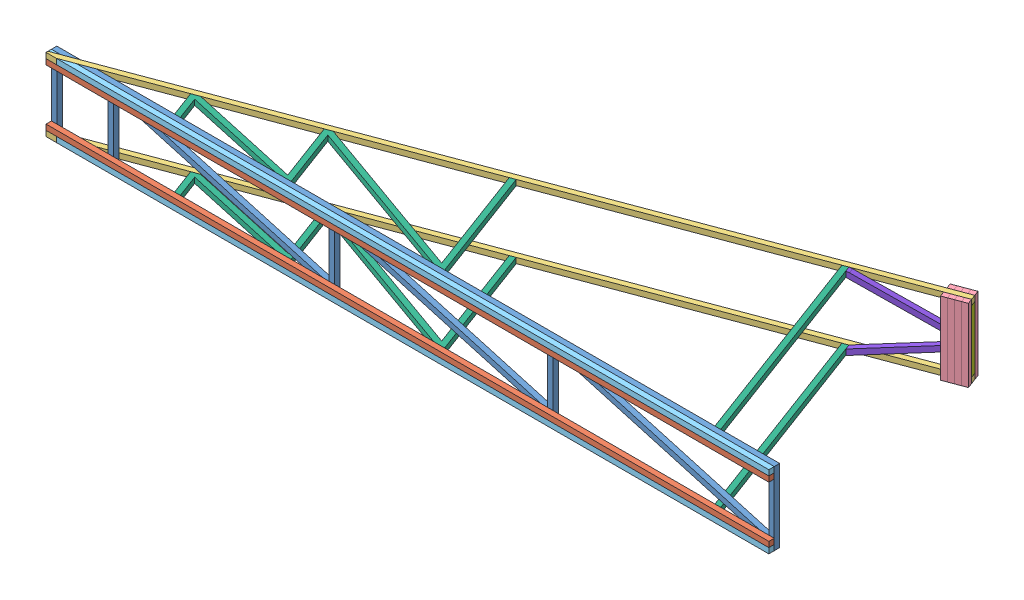
SolidWorks assembly boomAssembly3_1, configuration Default. Lengths in mm.
Overall size (423.17 42.7 151.68).
22 component instances, 9 part files, 96 mates.
Components (placement in the parent):
- cross brace compressionnew-1: cross brace compressionnew [Default] at (-109.2004 207.2528 347.8228) size (423.18 42.7 3.17)
- Part1-1: Part1 [Default] at (-109.2004 207.2528 354.1728) size (423.18 36.35 3.17)
- tension members-3: tension members [Default] at (269.1249 227.7278 350.9978) x (-1 0 0) z (0 0 1) size (396.18 3.18 148.71)
- tension members-4: tension members [Default] at (269.1249 267.2528 350.9978) x (-1 0 0) z (0 0 1) size (396.18 3.18 148.71)
- jHookMount-1: jHookMount [Default] at (264.7186 215.9028 209.7497) x (0.936777 0 -0.349926) z (0 1 0) size (3.17 3.17 42.7)
- jHookMount-2: jHookMount [Default] at (266.9407 215.9028 215.6982) x (0.936777 0 -0.349926) z (0 1 0) size (3.17 3.17 42.7)
- Part1^boomAssembly3_1-1: Part1^boomAssembly3_1 [Default] at origin (virtual)
- Part2^boomAssembly3_1-1: Part2^boomAssembly3_1 [Default] at (269.1249 258.6028 350.9978) x (1 0 0) z (0 1 0) size (423.17 3.17 3.17) (virtual)
- Part4^boomAssembly3_1-1: Part4^boomAssembly3_1 [Default] at (269.1249 258.6028 350.9978) x (1 0 0) z (0 1 0) size (325.36 119.85 3.17) (virtual)
- Part2^boomAssembly3_1-2: Part2^boomAssembly3_1 [Default] at (269.1249 219.0778 350.9978) x (1 0 0) z (0 1 0) size (423.17 3.17 3.17) (virtual)
- Part4^boomAssembly3_1-2: Part4^boomAssembly3_1 [Default] at (269.1249 219.0778 350.9978) x (1 0 0) z (0 1 0) size (325.36 119.85 3.17) (virtual)
- jHookMount-8: jHookMount [Default] at (261.7444 215.9028 210.8607) x (0.936777 0 -0.349926) z (0 1 0) size (3.17 3.17 42.7)
- jHookMount-9: jHookMount [Default] at (265.8296 215.9028 212.724) x (-0.936777 0 0.349926) z (0 1 0) size (3.17 3.17 42.7)
- jHookMount-10: jHookMount [Default] at (258.7701 215.9028 211.9717) x (0.936777 0 -0.349926) z (0 1 0) size (3.17 3.17 42.7)
- jHookMount-11: jHookMount [Default] at (260.9921 215.9028 217.9203) x (0.936777 0 -0.349926) z (0 1 0) size (3.17 3.17 42.7)
- Part5^boomAssembly3_1-1: Part5^boomAssembly3_1 [Default] at (267.6929 215.9028 208.6387) x (0 -1 0) z (0.936777 0 -0.349926) size (36.35 3.17 3.17) (virtual)
- Part5^boomAssembly3_1-2: Part5^boomAssembly3_1 [Default] at (264.7186 215.9028 209.7497) x (0 -1 0) z (0.936777 0 -0.349926) size (36.35 3.17 3.17) (virtual)
- Part5^boomAssembly3_1-3: Part5^boomAssembly3_1 [Default] at (261.7444 215.9028 210.8607) x (0 -1 0) z (0.936777 0 -0.349926) size (36.35 3.17 3.17) (virtual)
- jHookMount-16: jHookMount [Default] at (258.0179 215.9028 219.0313) x (0.936777 0 -0.349926) z (0 1 0) size (3.17 3.17 42.7)
- jHookMount-17: jHookMount [Default] at (255.7958 215.9028 213.0827) x (0.936777 0 -0.349926) z (0 1 0) size (3.17 3.17 42.7)
- Part9^boomAssembly3_1-1: Part9^boomAssembly3_1 [Default] at (223.3948 267.2528 228.5752) x (-0.936777 0 0.349926) z (0.349926 0 0.936777) size (43.13 42.7 3.17) (virtual)
- Part5^boomAssembly3_1-5: Part5^boomAssembly3_1 [Default] at (258.7701 215.9028 211.9717) x (0 -1 0) z (0.936777 0 -0.349926) size (36.35 3.17 3.17) (virtual)
Mates (geometry in assembly coordinates):
- Coincident4: coincident: plane of cross brace compressionnew-1 through (-127.3754 207.2528 350.9978) normal (-1 0 0); plane of Part1-1 through (-127.3754 207.2528 357.3478) normal (-1 0 0)
- Coincident5: coincident: plane of cross brace compressionnew-1 through (-109.2004 207.2528 354.1728) normal (0 0 1); plane of Part1-1 through (-109.2004 207.2528 354.1728) normal (0 0 -1)
- Coincident7: coincident: plane of Part1-1 through (-109.2004 207.2528 357.3478) normal (0 0 1); plane of tension members-3 through (291.79 227.7278 357.3478) normal (0 0 1)
- Coincident8: coincident: plane of cross brace compressionnew-1 through (-107.5644 219.0778 352.2026) normal (-0.349926 0 -0.936777); plane of tension members-3 through (223.3948 176.3778 228.5752) normal (0.349926 0 0.936777)
- Coincident9: coincident: plane of Part1-1 through (-109.2004 219.0778 357.3478) normal (0 -1 0); plane of tension members-3 through (291.79 219.0778 350.9978) normal (0 1 0)
- Coincident10: coincident: plane of cross brace compressionnew-1 through (-108.6754 255.4278 349.2284) normal (0.349926 0 0.936777); plane of tension members-4 through (222.2837 215.9028 225.6009) normal (-0.349926 0 -0.936777)
- Coincident11: coincident: plane of Part1-1 through (-109.2004 207.2528 357.3478) normal (0 0 1); plane of tension members-4 through (291.79 267.2528 357.3478) normal (0 0 1)
- Coincident12: coincident: plane of cross brace compressionnew-1 through (-131.8656 258.6028 347.8228) normal (0 1 0); plane of tension members-4 through (291.79 258.6028 350.9978) normal (0 1 0)
- Coincident13: coincident: plane of cross brace compressionnew-1 through (-131.8656 219.0778 347.8228) normal (0 1 0); plane of Part1-1 through (-109.2004 219.0778 357.3478) normal (0 -1 0)
- Coincident14: coincident: plane of tension members-3 through (222.2837 176.3778 225.6009) normal (-0.349926 0 -0.936777); plane of jHookMount-1 through (264.7186 258.6028 209.7497) normal (0.349926 0 0.936777)
- Coincident15: coincident: plane of tension members-4 through (291.79 258.6028 350.9978) normal (0 1 0); plane of jHookMount-1 through (264.7186 258.6028 209.7497) normal (0 1 0)
- Coincident17: coincident: plane of tension members-3 through (223.3948 176.3778 228.5752) normal (0.349926 0 0.936777); plane of jHookMount-2 through (265.8296 258.6028 212.724) normal (-0.349926 0 -0.936777)
- Coincident19: coincident: plane of tension members-3 through (291.79 215.9028 350.9978) normal (0 -1 0); plane of jHookMount-2 through (266.9407 215.9028 215.6982) normal (0 -1 0)
- InPlace1: in place: plane of tension members-4 through (291.79 258.6028 350.9978) normal (0 1 0); plane of ? through (0 258.6028 0) normal (0 1 0); moOrthogonalPlaneRef_w of tension members-4 through (291.79 258.6028 350.9978) normal (0 1 0); plane of ? through (0 258.6028 0) normal (0 0 -1); plane of tension members-4 through (291.79 258.6028 350.9978) normal (0 1 0); plane of ? through (0 258.6028 0) normal (1 0 0); plane of tension members-4 through (291.79 258.6028 350.9978) normal (0 1 0); unknown of ?
- Coincident20: coincident: plane of tension members-4; plane of Part2^boomAssembly3_1-1
- Coincident21: coincident: moOrthogonalPlaneRef_w of tension members-4 through (269.1249 258.6028 350.9978) normal (0 0 -1); plane of Part2^boomAssembly3_1-1 through (269.1249 258.6028 350.9978) normal (0 0 -1)
- Coincident22: coincident: moOrthogonalPlaneRef_w of tension members-4 through (269.1249 258.6028 350.9978) normal (-1 0 0); plane of Part2^boomAssembly3_1-1 through (269.1249 258.6028 350.9978) normal (1 0 0)
- Coincident23: coincident: plane of Part1-1 through (-109.2004 222.2528 357.3478) normal (0 1 0); plane of ? through (-109.2004 222.2528 360.5228) normal (0 1 0)
- Coincident24: coincident: plane of Part1-1 through (-109.2004 207.2528 357.3478) normal (0 0 1); plane of ? through (-109.2004 207.2528 357.3478) normal (0 0 -1)
- Coincident25: coincident: plane of cross brace compressionnew-1 through (-127.3754 207.2528 350.9978) normal (-1 0 0); plane of ? through (-127.3754 207.2528 360.5228) normal (-1 0 0)
- InPlace2: in place: plane of ? through (-127.3754 207.2528 360.5228) normal (-1 0 0); plane of ? through (-127.3754 0 0) normal (-1 0 0); plane of ? through (-127.3754 207.2528 360.5228) normal (-1 0 0); plane of ? through (-127.3754 0 0) normal (0 1 0); plane of ? through (-127.3754 207.2528 360.5228) normal (-1 0 0); plane of ? through (-127.3754 0 0) normal (0 0 1); plane of ? through (-127.3754 207.2528 360.5228) normal (-1 0 0); unknown of ?
- Coincident26: coincident: plane of ?; plane of ?
- Coincident27: coincident: moOrthogonalPlaneRef_w of ? through (-127.3754 207.2528 357.3478) normal (0 1 0); plane of ? through (-127.3754 207.2528 357.3478) normal (0 1 0)
- Coincident28: coincident: moOrthogonalPlaneRef_w of ? through (-127.3754 207.2528 357.3478) normal (0 0 -1); plane of ? through (-127.3754 207.2528 357.3478) normal (0 0 1)
- InPlace3: in place: plane of tension members-4 through (291.79 258.6028 350.9978) normal (0 1 0); plane of ? through (0 258.6028 0) normal (0 1 0); plane of tension members-4 through (291.79 258.6028 350.9978) normal (0 1 0); plane of ? through (0 258.6028 0) normal (0 0 -1); plane of tension members-4 through (291.79 258.6028 350.9978) normal (0 1 0); plane of ? through (0 258.6028 0) normal (1 0 0); plane of tension members-4 through (291.79 258.6028 350.9978) normal (0 1 0); unknown of ?
- Coincident29: coincident: plane of tension members-4; plane of Part4^boomAssembly3_1-1
- Coincident30: coincident: moOrthogonalPlaneRef_w of tension members-4 through (269.1249 258.6028 350.9978) normal (0 0 -1); plane of Part4^boomAssembly3_1-1 through (269.1249 258.6028 350.9978) normal (0 0 -1)
- Coincident31: coincident: moOrthogonalPlaneRef_w of tension members-4 through (269.1249 258.6028 350.9978) normal (-1 0 0); plane of Part4^boomAssembly3_1-1 through (269.1249 258.6028 350.9978) normal (1 0 0)
- Coincident32: coincident: plane of tension members-4 through (314.534 267.2528 334.0356) normal (0.936777 0 -0.349926); plane of jHookMount-1 through (267.6929 258.6028 208.6387) normal (0.936777 0 -0.349926)
- Coincident33: coincident: plane of tension members-4 through (314.534 267.2528 334.0356) normal (0.936777 0 -0.349926); plane of jHookMount-2 through (269.9149 258.6028 214.5872) normal (0.936777 0 -0.349926)
- Coincident34: coincident: plane of tension members-4 through (223.3948 215.9028 228.5752) normal (0.349926 0 0.936777); plane of jHookMount-11 through (259.8811 258.6028 214.946) normal (-0.349926 0 -0.936777)
- Coincident35: coincident: plane of tension members-4 through (223.3948 215.9028 228.5752) normal (0.349926 0 0.936777); plane of jHookMount-9 through (265.8296 258.6028 212.724) normal (-0.349926 0 -0.936777)
- Coincident36: coincident: plane of tension members-3 through (291.79 215.9028 350.9978) normal (0 -1 0); plane of jHookMount-9 through (265.8296 215.9028 212.724) normal (0 -1 0)
- Coincident37: coincident: plane of tension members-3 through (291.79 215.9028 350.9978) normal (0 -1 0); plane of jHookMount-11 through (260.9921 215.9028 217.9203) normal (0 -1 0)
- Coincident38: coincident: plane of tension members-3 through (222.2837 176.3778 225.6009) normal (-0.349926 0 -0.936777); plane of jHookMount-8 through (261.7444 258.6028 210.8607) normal (0.349926 0 0.936777)
- Coincident39: coincident: plane of tension members-3 through (222.2837 176.3778 225.6009) normal (-0.349926 0 -0.936777); plane of jHookMount-10 through (258.7701 258.6028 211.9717) normal (0.349926 0 0.936777)
- Coincident40: coincident: plane of tension members-3 through (291.79 215.9028 350.9978) normal (0 -1 0); plane of jHookMount-8 through (261.7444 215.9028 210.8607) normal (0 -1 0)
- Coincident41: coincident: plane of tension members-3 through (291.79 215.9028 350.9978) normal (0 -1 0); plane of jHookMount-10 through (258.7701 215.9028 211.9717) normal (0 -1 0)
- Coincident42: coincident: plane of jHookMount-1 through (264.7186 258.6028 209.7497) normal (-0.936777 0 0.349926); plane of jHookMount-8 through (264.7186 258.6028 209.7497) normal (0.936777 0 -0.349926)
- Coincident43: coincident: plane of jHookMount-8 through (261.7444 258.6028 210.8607) normal (-0.936777 0 0.349926); plane of jHookMount-10 through (261.7444 258.6028 210.8607) normal (0.936777 0 -0.349926)
- Coincident44: coincident: plane of jHookMount-2 through (266.9407 258.6028 215.6982) normal (-0.936777 0 0.349926); plane of jHookMount-9 through (265.8296 258.6028 212.724) normal (0.936777 0 -0.349926)
- Coincident45: coincident: plane of jHookMount-9 through (262.8554 258.6028 213.835) normal (-0.936777 0 0.349926); plane of jHookMount-11 through (263.9664 258.6028 216.8092) normal (0.936777 0 -0.349926)
- InPlace4: in place: plane of jHookMount-8 through (264.7186 258.6028 209.7497) normal (0.936777 0 -0.349926); plane of ? through (163.5476 0 -61.092) normal (0.936777 0 -0.349926); plane of jHookMount-8 through (264.7186 258.6028 209.7497) normal (0.936777 0 -0.349926); plane of ? through (163.5476 0 -61.092) normal (0 1 0); plane of jHookMount-8 through (264.7186 258.6028 209.7497) normal (0.936777 0 -0.349926); plane of ? through (163.5476 0 -61.092) normal (-0.349926 0 -0.936777); plane of jHookMount-1 through (267.6929 258.6028 208.6387) normal (0.936777 0 -0.349926); unknown of Part5^boomAssembly3_1-1
- Coincident46: coincident: plane of ?; plane of Part5^boomAssembly3_1-1
- Coincident47: coincident: moOrthogonalPlaneRef_w of jHookMount-1 through (267.6929 215.9028 208.6387) normal (-0.349926 0 -0.936777); plane of Part5^boomAssembly3_1-1 through (267.6929 215.9028 208.6387) normal (-0.349926 0 -0.936777)
- Coincident48: coincident: moOrthogonalPlaneRef_w of jHookMount-1 through (267.6929 215.9028 208.6387) normal (0 1 0); plane of Part5^boomAssembly3_1-1 through (267.6929 215.9028 208.6387) normal (0 -1 0)
- Coincident49: coincident: plane of tension members-4 through (291.79 255.4278 350.9978) normal (0 -1 0); plane of Part5^boomAssembly3_1-2 through (261.7444 255.4278 210.8607) normal (0 1 0)
- Coincident50: coincident: plane of Part5^boomAssembly3_1-1 through (264.7186 215.9028 209.7497) normal (-0.936777 0 0.349926); plane of Part5^boomAssembly3_1-2 through (264.7186 215.9028 209.7497) normal (0.936777 0 -0.349926)
- Coincident51: coincident: plane of jHookMount-8 through (261.7444 258.6028 210.8607) normal (0.349926 0 0.936777); plane of Part5^boomAssembly3_1-2 through (261.7444 255.4278 210.8607) normal (-0.349926 0 -0.936777)
- Coincident52: coincident: plane of jHookMount-10 through (258.7701 258.6028 211.9717) normal (0.349926 0 0.936777); plane of Part5^boomAssembly3_1-3 through (258.7701 255.4278 211.9717) normal (-0.349926 0 -0.936777)
- Coincident53: coincident: plane of tension members-4 through (291.79 255.4278 350.9978) normal (0 -1 0); plane of Part5^boomAssembly3_1-3 through (258.7701 255.4278 211.9717) normal (0 1 0)
- Coincident54: coincident: plane of Part5^boomAssembly3_1-2 through (261.7444 215.9028 210.8607) normal (-0.936777 0 0.349926); plane of Part5^boomAssembly3_1-3 through (261.7444 215.9028 210.8607) normal (0.936777 0 -0.349926)
- Coincident55: coincident: plane of jHookMount-2 through (266.9407 258.6028 215.6982) normal (0.936777 0 -0.349926); plane of ? through (265.8296 212.7278 212.724) normal (-0.936777 0 0.349926)
- Coincident56: coincident: plane of tension members-3 through (223.3948 176.3778 228.5752) normal (0.349926 0 0.936777); plane of ? through (265.8296 252.2528 212.724) normal (-0.349926 0 -0.936777)
- Coincident57: coincident: plane of jHookMount-2 through (263.9664 215.9028 216.8092) normal (0 -1 0); plane of ? through (265.8296 215.9028 212.724) normal (0 -1 0)
- Coincident58: coincident: plane of Part5^boomAssembly3_1-1 through (267.6929 215.9028 208.6387) normal (0.936777 0 -0.349926); plane of ? through (267.6929 215.9028 208.6387) normal (-0.936777 0 0.349926)
- Coincident59: coincident: plane of tension members-3 through (291.79 219.0778 350.9978) normal (0 1 0); plane of ? through (267.6929 219.0778 208.6387) normal (0 -1 0)
- Coincident60: coincident: plane of tension members-3 through (222.2837 176.3778 225.6009) normal (-0.349926 0 -0.936777); plane of ? through (267.6929 255.4278 208.6387) normal (-0.349926 0 -0.936777)
- Coincident61: coincident: plane of tension members-3 through (291.79 215.9028 350.9978) normal (0 -1 0); plane of ? through (268.8039 215.9028 211.6129) normal (0 -1 0)
- Coincident62: coincident: plane of Part5^boomAssembly3_1-1 through (267.6929 215.9028 208.6387) normal (0.936777 0 -0.349926); plane of ? through (268.8039 258.6028 211.6129) normal (-0.936777 0 0.349926)
- Coincident63: coincident: plane of tension members-3 through (222.2837 176.3778 225.6009) normal (-0.349926 0 -0.936777); plane of ? through (267.6929 258.6028 208.6387) normal (-0.349926 0 -0.936777)
- Coincident64: coincident: plane of ? through (271.7782 258.6028 210.5019) normal (0.936777 0 -0.349926); plane of ? through (270.6672 258.6028 207.5277) normal (0.936777 0 -0.349926)
- Coincident65: coincident: plane of ? through (271.7782 258.6028 210.5019) normal (0.936777 0 -0.349926); plane of ? through (272.8862 258.6028 213.4681) normal (0.936777 0 -0.349926)
- Coincident66: coincident: plane of ? through (268.8039 215.9028 211.6129) normal (0 -1 0); plane of ? through (267.6929 215.9028 208.6387) normal (0 -1 0)
- Coincident67: coincident: plane of ? through (268.8039 215.9028 211.6129) normal (0 -1 0); plane of ? through (269.9119 215.9028 214.5791) normal (0 -1 0)
- Coincident68: coincident: plane of ? through (267.6929 258.6028 208.6387) normal (-0.349926 0 -0.936777); plane of ? through (267.6929 258.6028 208.6387) normal (0.349926 0 0.936777)
- InPlace5: in place: plane of tension members-3 through (222.2837 176.3778 225.6009) normal (-0.349926 0 -0.936777); plane of ? through (101.171 0 270.8417) normal (-0.349926 0 -0.936777); plane of tension members-3 through (222.2837 176.3778 225.6009) normal (-0.349926 0 -0.936777); plane of ? through (101.171 0 270.8417) normal (0 1 0); plane of tension members-3 through (222.2837 176.3778 225.6009) normal (-0.349926 0 -0.936777); plane of ? through (101.171 0 270.8417) normal (-0.936777 0 0.349926); plane of tension members-3 through (222.2837 176.3778 225.6009) normal (-0.349926 0 -0.936777); unknown of ?
- Coincident69: coincident: plane of tension members-3; plane of ?
- Coincident70: coincident: moOrthogonalPlaneRef_w of tension members-3 through (222.2837 227.7278 225.6009) normal (0 -1 0); plane of ? through (222.2837 227.7278 225.6009) normal (0 -1 0)
- Coincident71: coincident: moOrthogonalPlaneRef_w of tension members-3 through (222.2837 227.7278 225.6009) normal (-0.936777 0 0.349926); plane of ? through (222.2837 227.7278 225.6009) normal (0.936777 0 -0.349926)
- Coincident72: coincident: plane of ? through (223.3948 215.9028 228.5752) normal (0.349926 0 0.936777); plane of jHookMount-16 through (256.9068 258.6028 216.057) normal (-0.349926 0 -0.936777)
- Coincident73: coincident: plane of tension members-3 through (222.2837 176.3778 225.6009) normal (-0.349926 0 -0.936777); plane of jHookMount-17 through (255.7958 258.6028 213.0827) normal (0.349926 0 0.936777)
- Coincident74: coincident: plane of jHookMount-11 through (260.9921 215.9028 217.9203) normal (0 -1 0); plane of jHookMount-16 through (258.0179 215.9028 219.0313) normal (0 -1 0)
- Coincident75: coincident: plane of tension members-3 through (291.79 215.9028 350.9978) normal (0 -1 0); plane of jHookMount-17 through (255.7958 215.9028 213.0827) normal (0 -1 0)
- Coincident76: coincident: plane of jHookMount-10 through (258.7701 258.6028 211.9717) normal (-0.936777 0 0.349926); plane of jHookMount-17 through (258.7701 258.6028 211.9717) normal (0.936777 0 -0.349926)
- Coincident77: coincident: plane of jHookMount-11 through (260.9921 258.6028 217.9203) normal (-0.936777 0 0.349926); plane of jHookMount-16 through (260.9921 258.6028 217.9203) normal (0.936777 0 -0.349926)
- InPlace6: in place: plane of tension members-3 through (222.2837 176.3778 225.6009) normal (-0.349926 0 -0.936777); plane of ? through (101.171 0 270.8417) normal (-0.349926 0 -0.936777); plane of tension members-3 through (222.2837 176.3778 225.6009) normal (-0.349926 0 -0.936777); plane of ? through (101.171 0 270.8417) normal (0 1 0); plane of tension members-3 through (222.2837 176.3778 225.6009) normal (-0.349926 0 -0.936777); plane of ? through (101.171 0 270.8417) normal (-0.936777 0 0.349926); plane of tension members-3 through (222.2837 176.3778 225.6009) normal (-0.349926 0 -0.936777); unknown of ?
- Coincident78: coincident: plane of tension members-3; plane of ?
- Coincident79: coincident: moOrthogonalPlaneRef_w of tension members-3 through (222.2837 227.7278 225.6009) normal (0 -1 0); plane of ? through (222.2837 227.7278 225.6009) normal (0 -1 0)
- Coincident80: coincident: moOrthogonalPlaneRef_w of tension members-3 through (222.2837 227.7278 225.6009) normal (-0.936777 0 0.349926); plane of ? through (222.2837 227.7278 225.6009) normal (0.936777 0 -0.349926)
- Coincident81: coincident: plane of jHookMount-16 through (258.0179 258.6028 219.0313) normal (-0.936777 0 0.349926); plane of ? through (256.9068 229.7528 216.057) normal (0.936777 0 -0.349926)
- Coincident82: coincident: plane of tension members-3 through (291.79 215.9028 350.9978) normal (0 -1 0); plane of ? through (233.0113 215.9028 224.983) normal (0 -1 0)
- Coincident83: coincident: plane of tension members-3 through (223.3948 176.3778 228.5752) normal (0.349926 0 0.936777); plane of ? through (223.3948 227.7278 228.5752) normal (-0.349926 0 -0.936777)
- InPlace7: in place: plane of tension members-4 through (223.3948 215.9028 228.5752) normal (0.349926 0 0.936777); plane of ? through (102.282 0 273.816) normal (0.349926 0 0.936777); plane of tension members-4 through (223.3948 215.9028 228.5752) normal (0.349926 0 0.936777); plane of ? through (102.282 0 273.816) normal (0 1 0); plane of tension members-4 through (223.3948 215.9028 228.5752) normal (0.349926 0 0.936777); plane of ? through (102.282 0 273.816) normal (0.936777 0 -0.349926); plane of tension members-4 through (223.3948 215.9028 228.5752) normal (0.349926 0 0.936777); unknown of Part9^boomAssembly3_1-1
- Coincident84: coincident: plane of tension members-4; plane of ?
- Coincident85: coincident: moOrthogonalPlaneRef_w of tension members-4 through (223.3948 267.2528 228.5752) normal (0 -1 0); plane of Part9^boomAssembly3_1-1 through (223.3948 267.2528 228.5752) normal (0 -1 0)
- Coincident86: coincident: moOrthogonalPlaneRef_w of tension members-4 through (223.3948 267.2528 228.5752) normal (0.936777 0 -0.349926); plane of Part9^boomAssembly3_1-1 through (223.3948 267.2528 228.5752) normal (-0.936777 0 0.349926)
- InPlace8: in place: plane of tension members-4 through (223.3948 215.9028 228.5752) normal (0.349926 0 0.936777); plane of ? through (102.282 0 273.816) normal (0.349926 0 0.936777); plane of tension members-4 through (223.3948 215.9028 228.5752) normal (0.349926 0 0.936777); plane of ? through (102.282 0 273.816) normal (0 1 0); plane of tension members-4 through (223.3948 215.9028 228.5752) normal (0.349926 0 0.936777); plane of ? through (102.282 0 273.816) normal (0.936777 0 -0.349926); plane of tension members-4 through (223.3948 215.9028 228.5752) normal (0.349926 0 0.936777); unknown of Part9^boomAssembly3_1-1
- Coincident87: coincident: plane of tension members-4; plane of Part9^boomAssembly3_1-1
- Coincident88: coincident: moOrthogonalPlaneRef_w of tension members-4 through (223.3948 267.2528 228.5752) normal (0 -1 0); plane of Part9^boomAssembly3_1-1 through (223.3948 267.2528 228.5752) normal (0 -1 0)
- Coincident89: coincident: moOrthogonalPlaneRef_w of tension members-4 through (223.3948 267.2528 228.5752) normal (0.936777 0 -0.349926); plane of Part9^boomAssembly3_1-1 through (223.3948 267.2528 228.5752) normal (-0.936777 0 0.349926)
- Coincident84: coincident: plane of tension members-4 through (291.79 255.4278 350.9978) normal (0 -1 0); plane of ? through (254.23 255.4278 217.0569) normal (0 1 0)
- Coincident85: coincident: plane of tension members-4 through (222.2837 215.9028 225.6009) normal (-0.349926 0 -0.936777); plane of ? through (253.119 255.4278 214.0826) normal (-0.349926 0 -0.936777)
- Coincident89: coincident: plane of tension members-4 through (291.79 255.4278 350.9978) normal (0 -1 0); plane of Part5^boomAssembly3_1-5 through (255.7958 255.4278 213.0827) normal (0 1 0)
- Coincident90: coincident: plane of tension members-4 through (222.2837 215.9028 225.6009) normal (-0.349926 0 -0.936777); plane of Part5^boomAssembly3_1-5 through (255.7958 255.4278 213.0827) normal (-0.349926 0 -0.936777)
- Coincident91: coincident: plane of Part5^boomAssembly3_1-3 through (258.7701 215.9028 211.9717) normal (-0.936777 0 0.349926); plane of Part5^boomAssembly3_1-5 through (258.7701 215.9028 211.9717) normal (0.936777 0 -0.349926)
